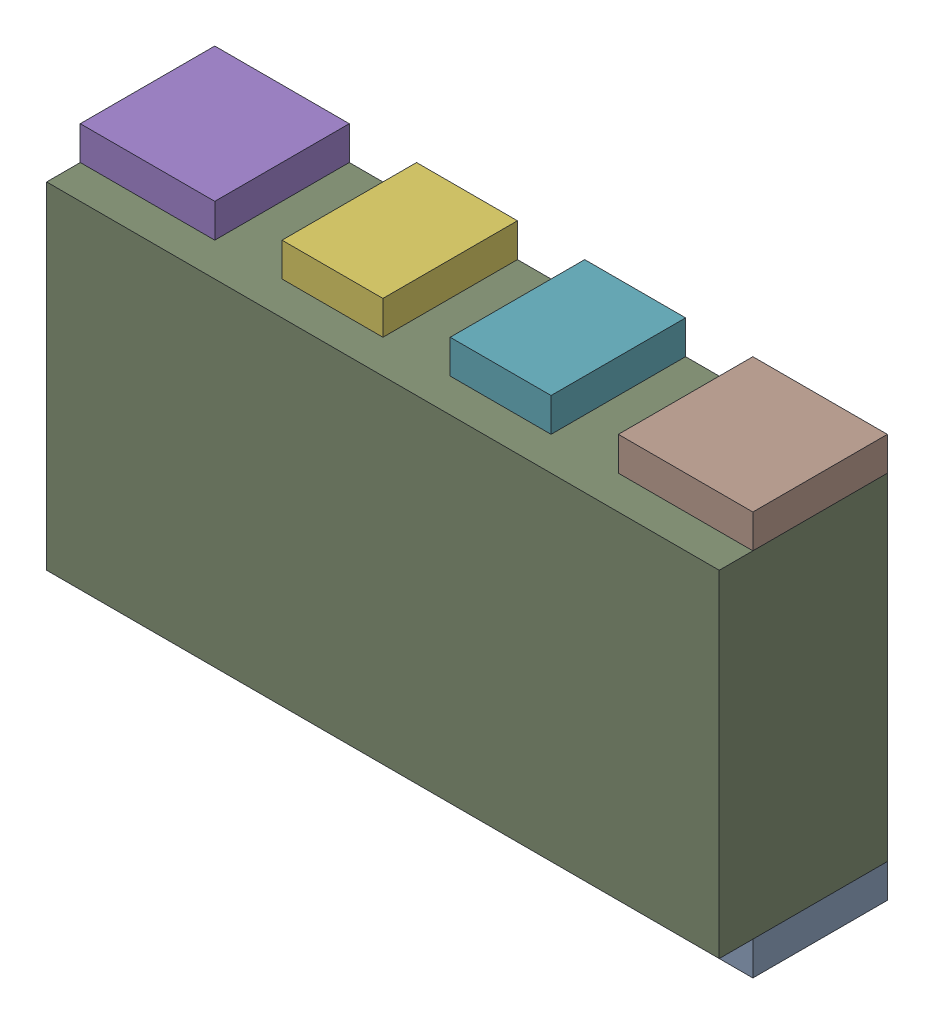
SolidWorks assembly RN15, configuration Default. Lengths in mm.
Overall size (2 1.2 0.5).
18 component instances, 3 part files, 0 mates.
Components (placement in the parent):
- 810157616-1: 810157616 [Default] at (130.8 61.85 0) size (0.4 0.1 0.4)
  - Extruded_12-1: Extruded_12 [Default] at origin size (0.4 0.1 0.4)
- 810157488-1: 810157488 [Default] at (130.25 61.85 0) size (0.3 0.1 0.4)
  - Extruded_19-1: Extruded_19 [Default] at origin size (0.3 0.1 0.4)
- 810157488-2: 810157488 [Default] at (129.75 61.85 0) size (0.3 0.1 0.4)
  - Extruded_19-1: Extruded_19 [Default] at origin size (0.3 0.1 0.4)
- 810157616-2: 810157616 [Default] at (129.2 61.85 0) size (0.4 0.1 0.4)
  - Extruded_12-1: Extruded_12 [Default] at origin size (0.4 0.1 0.4)
- 810157616-3: 810157616 [Default] at (129.2 62.95 0) size (0.4 0.1 0.4)
  - Extruded_12-1: Extruded_12 [Default] at origin size (0.4 0.1 0.4)
- 810157488-3: 810157488 [Default] at (129.75 62.95 0) size (0.3 0.1 0.4)
  - Extruded_19-1: Extruded_19 [Default] at origin size (0.3 0.1 0.4)
- 810157488-4: 810157488 [Default] at (130.25 62.95 0) size (0.3 0.1 0.4)
  - Extruded_19-1: Extruded_19 [Default] at origin size (0.3 0.1 0.4)
- 810157616-4: 810157616 [Default] at (130.8 62.95 0) size (0.4 0.1 0.4)
  - Extruded_12-1: Extruded_12 [Default] at origin size (0.4 0.1 0.4)
- 810158000-1: 810158000 [Default] at (130 62.4 0) size (2 1 0.5)
  - Extruded_20-1: Extruded_20 [Default] at origin size (2 1 0.5)
